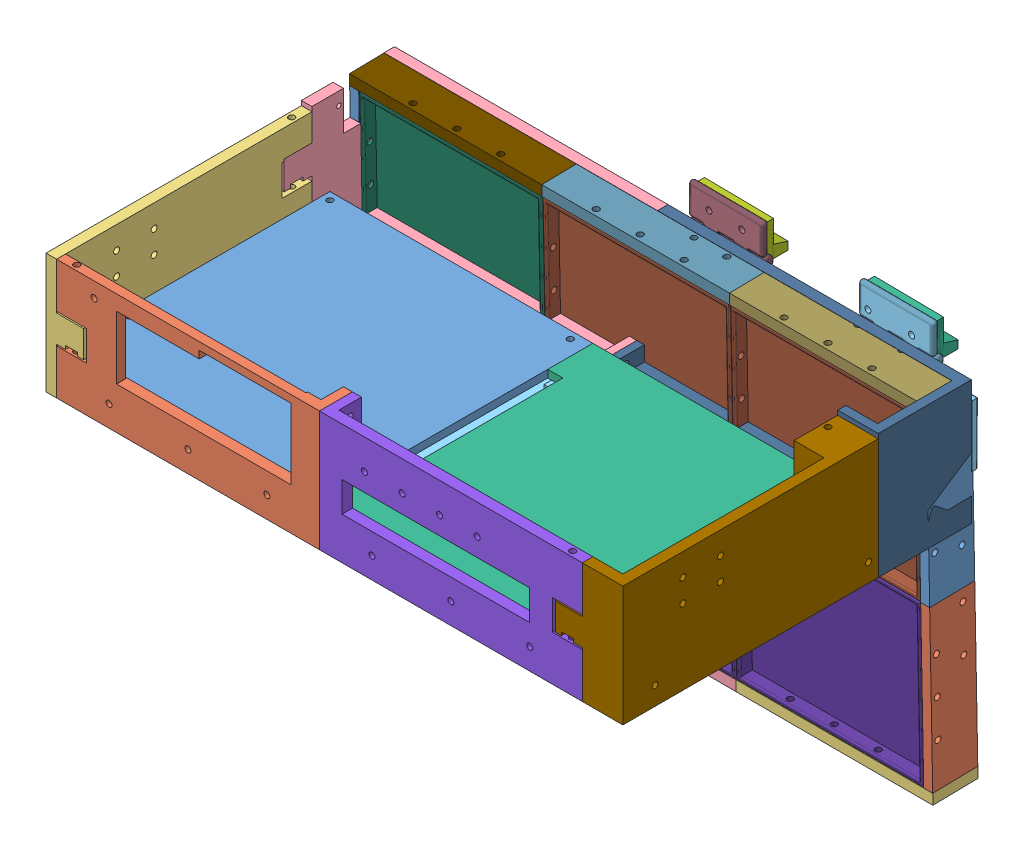
SolidWorks assembly complete, configuration Default. Lengths in mm.
Overall size (441 253.31 251).
30 component instances, 25 part files, 102 mates.
Components (placement in the parent):
- motherboardBase-1: motherboardBase [Default] at (-184.9548 -68.2026 67.3815) size (175 23 175)
- MotherboardFront-1: MotherboardFront [Default] at (-211.3841 -44.2096 189.267) x (-1 0 0) z (0 -1 0) size (175 22 80)
- MotherboardSide-1: MotherboardSide [Default] at (-303.5006 -50.9114 109.4373) x (0 0 -1) z (0 -1 0) size (170 25 80)
- psuContainment-1: psuContainment [Default] at (-258.6521 -91.2034 -19.3996) x (1 0 0) z (0 0 1) size (182 83 80.5)
- underMotherboard-1: underMotherboard [Default] at (-144.9542 -91.2034 87.8237) size (175 23 163)
- gpuBase-1: gpuBase [Default] at (-9.9548 -68.2026 67.3815) size (175 23 175)
- underGPU-2: underGPU [Default] at (205.0458 -91.2034 87.8237) size (175 23 163)
- gpuFront-1: gpuFront [Default] at (-211.3841 -44.2096 189.267) x (-1 0 0) z (0 -1 0) size (175 22 80)
- gpuSide-1: gpuSide [Default] at (60.4994 -50.9114 -70.9033) x (0 0 1) z (0 -1 0) size (170 45 80)
- gpuBackplate-1: gpuBackplate [Default] at (145.3479 -91.2034 -19.3996) x (1 0 0) z (0 0 1) size (259 83 80.5)
- CaseBase-6: CaseBase [Default] at (151.1093 -93.4415 -25.3379) x (1 0 0) z (0 -0.999822 -0.018865) size (125 11 110)
- TopHingeEdge-1: TopHingeEdge [Default] at (52.0098 -7.54 -77.8941) x (1 0 0) z (0 0.018865 -0.999822) size (131 7 30)
- closeHinge-1: closeHinge [Default] at (-43.2891 -37.8407 -16.9315) x (0.005688 0.999984 0) z (-0.999984 0.005688 0) size (72.57 8.04 78.74)
- CaseBase-8: CaseBase [Default] at (26.1093 -93.4415 -25.3379) x (1 0 0) z (0 -0.999822 -0.018865) size (125 11 110)
- MiddleHingeEdge-1: MiddleHingeEdge [Default] at (-72.9902 -7.54 -77.8941) x (1 0 0) z (0 0.018865 -0.999822) size (125 7 30)
- CaseBaseBackCorner-1: CaseBaseBackCorner [Default] at (-95.8907 -93.4415 -25.3379) x (1 0 0) z (0 -0.999822 -0.018865) size (122 11 110)
- caseBaseFrontCorner-1: caseBaseFrontCorner [Default] at (-95.8907 -203.4219 -27.4131) x (1 0 0) z (0 -0.999822 -0.018865) size (122 11 108)
- CaseBaseFront-1: CaseBaseFront [Default] at (26.1093 -203.4219 -27.4131) x (1 0 0) z (0 -0.999822 -0.018865) size (125 11 108)
- CaseBaseFront-2: CaseBaseFront [Default] at (151.1093 -203.4219 -27.4131) x (1 0 0) z (0 -0.999822 -0.018865) size (125 11 108)
- MoboSideEdge-1: MoboSideEdge [Default] at (-200.9902 -7.54 -77.8941) x (1 0 0) z (0 0.018865 -0.999822) size (128 7 30)
- MoboSideEdge-2: MoboSideEdge [Default] at (-200.9902 -232.4999 -82.1388) x (1 0 0) z (0 0.018865 -0.999822) size (128 7 30)
- SideEdge-1: SideEdge [Default] at (-303.5006 -22.0269 -78.1674) x (0 0.999822 0.018865) z (0 0.018865 -0.999822) size (110 6 30)
- SideEdge-3: SideEdge [Default] at (80.4994 -117.0309 -79.96) x (0 -0.999822 -0.018865) z (0 0.018865 -0.999822) size (110 6 30)
- FrontSideEdge-1: FrontSideEdge [Default] at (-297.5006 -227.0114 -82.0352) x (0 -0.999822 -0.018865) z (0 0.018865 -0.999822) size (108 6 30)
- FrontSideEdge-2: FrontSideEdge [Default] at (80.4994 -227.0113 -82.0352) x (0 -0.999822 -0.018865) z (0 0.018865 -0.999822) size (108 6 30)
- FrontTopHingeEdge-1: FrontTopHingeEdge [Default] at (52.0098 -232.4999 -82.1388) x (1 0 0) z (0 0.018865 -0.999822) size (131 7 30)
- FrontMiddleHingeEdge-1: FrontMiddleHingeEdge [Default] at (-72.9902 -232.4999 -82.1388) x (1 0 0) z (0 0.018865 -0.999822) size (125 7 30)
- sideCloseHinge-1: sideCloseHinge [Default] at (69.9187 -38.4847 -16.9315) x (0.005688 0.999984 0) z (-0.999984 0.005688 0) size (72.57 8.04 78.74)
- standup_side-2: standup_side [Default] at (28.8834 -2.7579 -46.733) x (-0.999912 0.013238 0) z (-0.013238 -0.999912 0) size (46 15 23.5)
- standup_middle-1: standup_middle [Default] at (-84.3085 -2.4535 -46.733) x (-0.999912 0.013238 0) z (-0.013238 -0.999912 0) size (46 15 23.5)
Mates (geometry in assembly coordinates):
- Coincident2: coincident anti-aligned: circle of motherboardBase-1; circle of underMotherboard-1
- Coincident3: coincident anti-aligned: circle of psuContainment-1; circle of underMotherboard-1
- Coincident8: coincident anti-aligned: line of MotherboardFront-1 through (-121.5006 -91.2026 182.267) axis (-1 0 0); line of underMotherboard-1 through (-296.5006 -91.2034 182.267) axis (1 0 0)
- Coincident9: coincident anti-aligned: line of motherboardBase-1 through (-296.5006 -63.2026 182.267) axis (1 0 0); line of MotherboardFront-1 through (-136.5006 -63.2026 182.267) axis (-1 0 0)
- Coincident10: coincident anti-aligned: line of motherboardBase-1 through (-296.5006 -63.2026 182.267) axis (0 -1 0); line of MotherboardFront-1 through (-296.5006 -91.2026 182.267) axis (0 1 0)
- Coincident12: coincident anti-aligned: line of MotherboardSide-1 through (-296.5006 -91.2034 189.267) axis (0 0 -1); line of underMotherboard-1 through (-296.5006 -91.2034 19.267) axis (0 0 1)
- Parallel1: parallel anti-aligned: line of MotherboardFront-1 through (-276.5006 -61.2026 189.267) axis (0 1 0); line of MotherboardSide-1 through (-278.5006 -42.2034 189.267) axis (0 -1 0)
- Coincident14: coincident anti-aligned: line of MotherboardFront-1 through (-296.5006 -91.2026 189.267) axis (0 1 0); line of MotherboardSide-1 through (-296.5006 -60.2034 189.267) axis (0 -1 0)
- Coincident15: coincident anti-aligned: line of motherboardBase-1 through (-121.5006 -63.2026 182.267) axis (0 0 -1); line of gpuBase-1 through (-121.5006 -63.2026 152.267) axis (0 0 1)
- Coincident16: coincident aligned: line of motherboardBase-1 through (-121.5006 -63.2026 7.267) axis (0 -1 0); line of gpuBase-1 through (-121.5006 -63.2026 7.267) axis (0 -1 0)
- Coincident20: coincident aligned: circle of gpuBase-1; circle of underGPU-2
- Coincident27: coincident anti-aligned: plane of MotherboardFront-1 through (-121.5006 -11.2026 182.267) normal (1 0 0); plane of gpuFront-1 through (-121.5006 -11.2026 182.267) normal (-1 0 0)
- Coincident28: coincident aligned: line of MotherboardFront-1 through (-121.5006 -11.2026 189.267) axis (0 -1 0); line of gpuFront-1 through (-121.5006 -11.2026 189.267) axis (0 -1 0)
- Coincident29: coincident aligned: line of MotherboardFront-1 through (-121.5006 -11.2026 167.267) axis (0 0 1); line of gpuFront-1 through (-121.5006 -11.2026 167.267) axis (0 0 1)
- Coincident31: coincident anti-aligned: line of underGPU-2 through (53.4994 -91.2034 19.267) axis (0 0 1); line of gpuSide-1 through (53.4994 -91.2034 189.267) axis (0 0 -1)
- Coincident32: coincident anti-aligned: line of underGPU-2 through (53.4994 -91.2034 182.267) axis (-1 0 0); line of gpuFront-1 through (-121.5006 -91.2026 182.267) axis (1 0 0)
- Coincident34: coincident anti-aligned: plane of psuContainment-1 through (-121.5006 -86.2034 -42.733) normal (1 0 0); plane of gpuBackplate-1 through (-121.5006 -86.2034 -42.733) normal (-1 0 0)
- Coincident35: coincident anti-aligned: circle of underGPU-2; circle of gpuBackplate-1
- Concentric5: concentric aligned: circle of gpuBackplate-1; circle of backMount-1
- Concentric6: concentric anti-aligned: cylinder of gpuBackplate-1 through (25.4994 -53.2034 -117.733) axis (0 0 1) radius 2; circle of backMount-1
- Coincident36: coincident: plane of gpuBackplate-1 through (60.4994 -86.2034 -42.733) normal (0 0 -1); line of backMount-1 through (20.4994 -18.2034 -42.733) axis (1 0 0)
- Coincident37: coincident anti-aligned: plane of CaseBase-1 through (-176.5006 9.2441 72.267) normal (0 0 1); plane of CaseBase-2 through (-176.5006 9.2441 72.267) normal (0 0 -1)
- Coincident38: coincident aligned: line of CaseBase-1 through (-51.5006 8.2441 72.267) axis (0 -1 0); line of CaseBase-2 through (-51.5006 8.2441 72.267) axis (0 -1 0)
- Coincident39: coincident aligned: line of CaseBase-1 through (-51.5006 -1.7559 72.267) axis (0 0 -1); line of CaseBase-2 through (-51.5006 -1.7559 182.267) axis (0 0 -1)
- Coincident40: coincident aligned: line of CaseBase-4 through (-168.8885 17.2982 184.3005) axis (0 0 -1); line of CaseBase-5 through (-168.8885 17.2982 74.3005) axis (0 0 -1)
- Coincident41: coincident anti-aligned: plane of CaseBase-4 through (-292.689 37.7788 74.3005) normal (0 0 -1); plane of CaseBase-5 through (-292.689 37.7788 74.3005) normal (0 0 1)
- Coincident42: coincident aligned: line of CaseBase-4 through (-168.1275 27.2692 74.3005) axis (-0.0761 -0.9971 0); line of CaseBase-5 through (-168.1275 27.2692 74.3005) axis (-0.0761 -0.9971 0)
- Coincident47: coincident anti-aligned: plane of CaseBase-2 through (-176.5006 9.2441 72.267) normal (-1 0 0); plane of CaseBase-4 through (-168.0514 28.2663 74.3005) normal (0.9971 -0.0761 0)
- Coincident48: coincident aligned: line of CaseBase-1 through (-176.5006 8.2441 -37.733) axis (0 -1 0); line of CaseBase-5 through (-168.1275 27.2692 -35.6995) axis (-0.0761 -0.9971 0)
- Coincident49: coincident anti-aligned: line of CaseBase-1 through (-176.5006 -1.7559 -37.733) axis (0 0 1); line of CaseBase-5 through (-168.8885 17.2982 74.3005) axis (0 0 -1)
- Coincident50: coincident anti-aligned: line of CaseBase-1 through (-51.5006 8.2441 -37.733) axis (0 0 1); line of CaseBase-6 through (-50.5006 -125.7297 -15.9454) axis (0 0.999822 0.018865)
- Coincident51: coincident aligned: line of CaseBase-1 through (-51.5006 8.2441 -37.733) axis (0 -1 0); line of CaseBase-6 through (-50.5006 -15.7493 -13.8702) axis (0 0.018865 -0.999822)
- Coincident61: coincident anti-aligned: line of gpuSide-1 through (80.4994 -11.2034 19.267) axis (0 -1 0); line of gpuBackplate-1 through (80.4994 -91.2034 19.267) axis (0 1 0)
- Coincident68: coincident aligned: line of gpuBackplate-1 through (-121.5006 -8.2034 -42.733) axis (1 0 0); line of TopHingeEdge-1 through (-50.5006 -8.2034 -42.733) axis (1 0 0)
- Coincident70: coincident aligned: plane of CaseBase-6 through (151.1093 -93.649 -14.3399) normal (0 -0.018865 0.999822); plane of TopHingeEdge-1 through (-50.5006 -15.7681 -12.8704) normal (0 -0.018865 0.999822)
- Coincident71: coincident aligned: line of TopHingeEdge-1 through (-50.5006 -8.7694 -12.7383) axis (1 0 0); line of TopMount-1 through (6.9994 21.7966 -42.733) axis (1 0 0)
- Parallel8: parallel anti-aligned: plane of gpuBackplate-1 through (60.4994 -86.2034 -42.733) normal (0 0 -1); plane of backMount-1 through (28.8848 -30.4169 -42.733) normal (0 0 1)
- Coincident73: coincident anti-aligned: plane of TopHingeEdge-1 through (52.0098 -7.54 -77.8941) normal (0 0.999822 0.018865); plane of TopMount-1 through (15.3848 9.5831 -42.733) normal (0 0 1)
- Coincident74: coincident aligned: circle of TopHingeSupport-1; circle of TopMount-1
- Concentric7: concentric aligned: cylinder of backHinge-1 through (34.1008 6.7966 -44.733) axis (1 0 0) radius 2.5; cylinder of TopMount-1 through (15.3848 6.7966 -44.733) axis (1 0 0) radius 4
- Coincident77: coincident aligned: line of CaseBase-6 through (-50.5006 -15.7493 -13.8702) axis (0 0.018865 -0.999822); line of TopHingeEdge-1 through (-50.5006 -15.7681 -12.8704) axis (0 0.018865 -0.999822)
- Parallel10: parallel anti-aligned: plane of CaseBase-6 through (-50.5006 -15.7681 -12.8704) normal (0 0.999822 0.018865); plane of TopHingeEdge-1 through (52.0098 -14.5387 -78.0261) normal (0 -0.999822 -0.018865)
- Coincident78: coincident anti-aligned: plane of gpuBackplate-1 through (60.4994 -86.2034 -42.733) normal (0 0 -1); plane of closeHinge-1 through (-43.2891 -37.8407 -42.733) normal (0 0 1)
- Coincident79: coincident anti-aligned: plane of CaseBase-6 through (-50.5006 -15.7681 -12.8704) normal (-1 0 0); plane of CaseBase-8 through (-50.5006 -15.7681 -12.8704) normal (1 0 0)
- Concentric8: concentric aligned: circle of CaseBase-6; circle of CaseBase-8
- Concentric9: concentric anti-aligned: circle of CaseBase-6; cylinder of CaseBase-8 through (-175.5006 -45.6873 -17.4356) axis (1 0 0) radius 2
- Coincident83: coincident anti-aligned: plane of CaseBase-8 through (-175.5006 -15.7681 -12.8704) normal (0 0.999822 0.018865); plane of MiddleHingeEdge-1 through (-72.9902 -14.5387 -78.0261) normal (0 -0.999822 -0.018865)
- Concentric10: concentric anti-aligned: circle of CaseBase-8; circle of MiddleHingeSupport-1
- Concentric11: concentric anti-aligned: circle of CaseBase-8; circle of MiddleHingeSupport-1
- Coincident89: coincident anti-aligned: plane of CaseBase-8 through (-175.5006 -15.7681 -12.8704) normal (-1 0 0); plane of CaseBaseBackCorner-1 through (-175.5006 -15.7681 -12.8704) normal (1 0 0)
- Concentric14: concentric aligned: circle of CaseBase-8; circle of caseBaseBackCorner-1
- Concentric15: concentric aligned: circle of CaseBase-8; circle of caseBaseBackCorner-1
- Coincident92: coincident anti-aligned: plane of CaseBaseBackCorner-1 through (-297.5006 -125.7485 -14.9456) normal (0 -0.999822 -0.018865); plane of caseBaseFrontCorner-1 through (-297.5006 -125.7485 -14.9456) normal (0 0.999822 0.018865)
- Concentric16: concentric anti-aligned: circle of caseBaseBackCorner-1; circle of caseBaseFrontCorner-1
- Concentric17: concentric anti-aligned: circle of caseBaseBackCorner-1; circle of caseBaseFrontCorner-1
- Coincident95: coincident anti-aligned: plane of CaseBase-8 through (-175.5006 -125.7485 -14.9456) normal (0 -0.999822 -0.018865); plane of CaseBaseFront-1 through (-175.5006 -125.7485 -14.9456) normal (0 0.999822 0.018865)
- Concentric18: concentric anti-aligned: circle of CaseBase-8; circle of CaseBaseFront-1
- Concentric19: concentric anti-aligned: circle of CaseBase-8; circle of CaseBaseFront-1
- Coincident98: coincident anti-aligned: plane of CaseBase-6 through (-50.5006 -125.7485 -14.9456) normal (0 -0.999822 -0.018865); plane of CaseBaseFront-2 through (-50.5006 -125.7485 -14.9456) normal (0 0.999822 0.018865)
- Concentric20: concentric anti-aligned: circle of CaseBase-6; circle of CaseBaseFront-2
- Concentric21: concentric anti-aligned: circle of CaseBase-6; circle of CaseBaseFront-2
- Coincident99: coincident anti-aligned: plane of CaseBaseBackCorner-1 through (-297.5006 -15.7681 -12.8704) normal (0 0.999822 0.018865); plane of MoboSideEdge-1 through (-200.9902 -14.5387 -78.0261) normal (0 -0.999822 -0.018865)
- Concentric22: concentric anti-aligned: circle of caseBaseBackCorner-1; circle of MoboSideHinge-1
- Concentric23: concentric anti-aligned: circle of caseBaseBackCorner-1; circle of MoboSideHinge-1
- Parallel11: parallel aligned: plane of gpuBackplate-1 through (80.4994 -91.2034 -19.3996) normal (1 0 0); plane of TopHingeEdge-1 through (80.4994 -15.7681 -12.8704) normal (1 0 0)
- Coincident103: coincident aligned: plane of gpuBackplate-1 through (80.4994 -91.2034 -19.3996) normal (1 0 0); plane of TopHingeEdge-1 through (80.4994 -15.7681 -12.8704) normal (1 0 0)
- Concentric24: concentric anti-aligned: circle of caseBaseFrontCorner-1; circle of MoboSideHinge-2
- Concentric25: concentric anti-aligned: circle of caseBaseFrontCorner-1; circle of MoboSideHinge-2
- Concentric28: concentric anti-aligned: circle of CaseBaseBackCorner-1; circle of SideEdge-1
- Coincident111: coincident anti-aligned: plane of CaseBaseBackCorner-1 through (-297.5006 -15.7681 -12.8704) normal (-1 0 0); plane of SideEdge-1 through (-297.5006 -22.0269 -78.1674) normal (1 0 0)
- Coincident112: coincident: plane of caseBaseFrontCorner-1 through (-297.5006 -125.7485 -14.9456) normal (-1 0 0); plane of SideEdge-2 through (-297.5006 -43.3708 80.7566) normal (1 0 0)
- Concentric29: concentric: circle of caseBaseFrontCorner-1; circle of SideEdge-2
- Concentric30: concentric anti-aligned: circle of caseBaseFrontCorner-1; circle of SideEdge-2
- Coincident115: coincident anti-aligned: plane of CaseBase-6 through (74.4994 -15.7681 -12.8704) normal (1 0 0); plane of SideEdge-3 through (74.4994 -117.0309 -79.96) normal (-1 0 0)
- Concentric31: concentric aligned: circle of CaseBase-6; circle of SideEdge-3
- Concentric32: concentric aligned: circle of CaseBase-6; circle of SideEdge-3
- Coincident119: coincident anti-aligned: plane of caseBaseFrontCorner-1 through (-297.5006 -125.7485 -14.9456) normal (-1 0 0); plane of FrontSideEdge-1 through (-297.5006 -227.0114 -82.0352) normal (1 0 0)
- Concentric33: concentric aligned: circle of caseBaseFrontCorner-1; circle of FrontSideEdge-1
- Concentric34: concentric aligned: circle of caseBaseFrontCorner-1; circle of FrontSideEdge-1
- Coincident123: coincident anti-aligned: plane of CaseBaseFront-2 through (74.4994 -125.7485 -14.9456) normal (1 0 0); plane of FrontSideEdge-2 through (74.4994 -227.0113 -82.0352) normal (-1 0 0)
- Concentric36: concentric aligned: circle of CaseBaseFront-2; circle of FrontSideEdge-2
- Concentric37: concentric aligned: circle of CaseBaseFront-2; circle of FrontSideEdge-2
- Coincident127: coincident anti-aligned: plane of CaseBaseFront-2 through (-50.5006 -233.7293 -16.983) normal (0 -0.999822 -0.018865); plane of FrontTopHingeEdge-1 through (52.0098 -232.4999 -82.1388) normal (0 0.999822 0.018865)
- Concentric38: concentric anti-aligned: circle of CaseBaseFront-2; circle of FrontTopHingeEdge-1
- Concentric39: concentric anti-aligned: circle of CaseBaseFront-2; circle of FrontTopHingeEdge-1
- Coincident130: coincident anti-aligned: plane of CaseBaseFront-1 through (-175.5006 -233.7293 -16.983) normal (0 -0.999822 -0.018865); plane of FrontMiddleHingeEdge-1 through (-72.9902 -232.4999 -82.1388) normal (0 0.999822 0.018865)
- Concentric40: concentric anti-aligned: circle of CaseBaseFront-1; circle of FrontMiddleHingeEdge-1
- Concentric41: concentric anti-aligned: circle of CaseBaseFront-1; circle of FrontMiddleHingeEdge-1
- Coincident131: coincident anti-aligned: plane of gpuBackplate-1 through (60.4994 -86.2034 -42.733) normal (0 0 -1); plane of sideCloseHinge-1 through (69.9187 -38.4847 -42.733) normal (0 0 1)
- Concentric42: concentric anti-aligned: circle of gpuBackplate-1; circle of closeHinge-1
- Concentric43: concentric aligned: circle of gpuBackplate-1; circle of closeHinge-1
- Parallel16: parallel: line of closeHinge-1 through (-32.4164 -60.4294 -45.733) axis (0.005688 0.999984 0); plane of sideCloseHinge-1 through (80.7238 -72.9564 -42.733) normal (0.999984 -0.005688 0)
- Parallel17: parallel aligned: plane of closeHinge-1 through (-100.2236 -18.9568 -42.733) normal (0.005688 0.999984 0); plane of sideCloseHinge-1 through (12.9842 -19.6008 -42.733) normal (0.005688 0.999984 0)
- Coincident138: coincident aligned: plane of closeHinge-1 through (-100.2236 -18.9568 -42.733) normal (0.005688 0.999984 0); plane of sideCloseHinge-1 through (12.9842 -19.6008 -42.733) normal (0.005688 0.999984 0)
- Concentric45: concentric anti-aligned: circle of CaseBaseBackCorner-1; circle of SideEdge-1
- Coincident141: coincident anti-aligned: plane of caseBaseFrontCorner-1 through (-297.5006 -233.7293 -16.983) normal (0 -0.999822 -0.018865); plane of MoboSideEdge-2 through (-200.9902 -232.4999 -82.1388) normal (0 0.999822 0.018865)
- Coincident142: coincident anti-aligned: plane of sideCloseHinge-1 through (69.9187 -38.4847 -46.733) normal (0 0 -1); plane of standup_side-1 through (28.8634 -2.7793 -46.733) normal (0 0 1)
- Parallel18: parallel: line of sideCloseHinge-1 through (52.9811 9.6533 -46.733) axis (-0.999912 0.013238 0.000661); plane of standup_side-1 through (52.9562 9.633 -51.733) normal (0.013238 0.999912 0)
- Coincident148: coincident anti-aligned: plane of sideCloseHinge-1 through (69.9187 -38.4847 -46.733) normal (0 0 -1); plane of standup_side-2 through (28.8834 -2.7579 -46.733) normal (0 0 1)
- Parallel20: parallel: line of sideCloseHinge-1 through (52.9811 9.6533 -46.733) axis (-0.999912 0.013238 0.000661); plane of standup_side-2 through (52.9762 9.6543 -51.733) normal (0.013238 0.999912 0)
- Coincident152: coincident anti-aligned: plane of closeHinge-1 through (-43.2891 -37.8407 -46.733) normal (0 0 -1); plane of standup_middle-1 through (-84.3085 -2.4535 -46.733) normal (0 0 1)
- Parallel23: parallel: line of closeHinge-1 through (-60.2267 10.2972 -46.733) axis (-0.999912 0.013238 0.000661); plane of standup_middle-1 through (-60.2157 9.9587 -51.733) normal (0.013238 0.999912 0)
